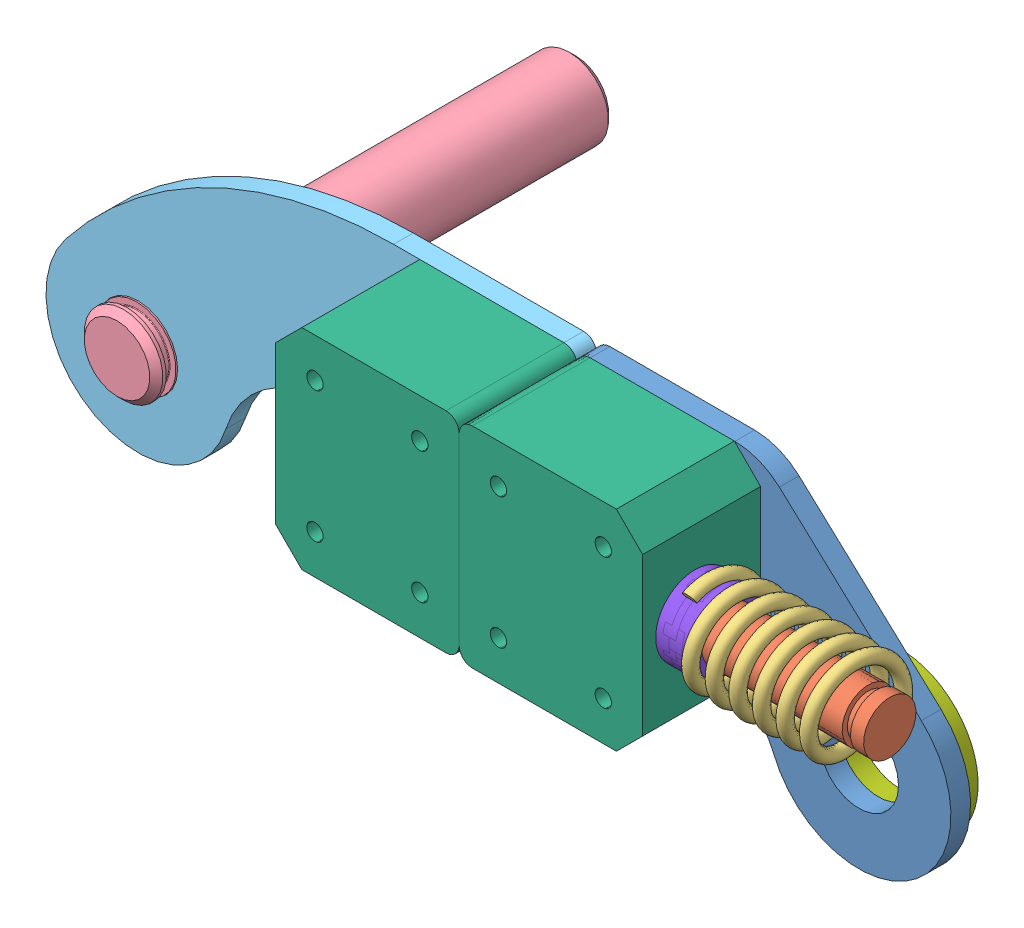
SolidWorks assembly Assem1-knee-mod2-front-mirror, configuration Défaut. Lengths in mm.
Overall size (71.29 24.64 43.49).
18 component instances, 10 part files, 31 mates.
Components (placement in the parent):
- Part1-knee-mod3-front-1: Part1-knee-mod3-front [Défaut] at (3.122 0.7472 0) size (28.52 23.53 1.5)
- part2-knee-mod1-1: part2-knee-mod1 [Default] at (-34.018 9.2472 5.75) x (0 0.169023 0.985612) z (0 0.985612 -0.169023) size (4 44.5 4)
- Spring_DF-1670-2: Spring_DF-1670 [Défaut] at (-2.378 9.2472 5.75) x (0 -0.202607 -0.97926) z (1 0 0) size (8.62 8.62 12.7)
- d5l35-1: d5l35 [Default] at (-51.878 0.7472 -32.65) x (1 0 0) z (0 -1 0) size (6 35 6)
- al_d6_1-2: al_d6_1 [Default] at (3.122 0.7472 -10.41) x (0.954097 0.299497 0) z (0.299497 -0.954097 0) size (6 13 6)
- lock washer for shafts_din-3: lock washer for shafts_din [PreviewCfg] at (-32.378 9.2472 5.75) x (0 0.148956 -0.988844) z (1 0 0) size (2.25 1.94 0.2)
- lock washer for shafts_din-4: lock washer for shafts_din [PreviewCfg] at (8.842 9.2472 5.75) x (0 -1 0) z (-1 0 0) size (2.25 1.94 0.2)
- lock washer for shafts_din-5: lock washer for shafts_din [PreviewCfg] at (-51.878 0.7472 1.05) size (2.25 1.94 0.2)
- lock washer for shafts_din-6: lock washer for shafts_din [PreviewCfg] at (3.122 0.7472 1.05) size (2.25 1.94 0.2)
- Part2-knee-mod3-front-1: Part2-knee-mod3-front [Défaut] at (-51.878 0.7472 0) x (-1 0 0) z (0 0 -1) size (40.53 23.53 1.5)
- part4-knee-mod1-1: part4-knee-mod1 [Défaut] at (-25.378 9.2472 5.75) x (0 1 0) z (-1 0 0) size (16 9 14)
- part4-knee-mod1-2: part4-knee-mod1 [Défaut] at (-11.378 9.2472 5.75) x (0 -1 0) z (1 0 0) size (16 9 14)
- Washer-d6p5-12-1: Washer-d6p5-12 [Défaut] at (-51.878 0.7472 -1.55) x (0.480416 0.877041 0) z (0 0 1) size (12 12 1.6)
- Washer-d6p5-12-2: Washer-d6p5-12 [Défaut] at (3.122 0.7472 -1.55) x (0.480416 0.877041 0) z (0 0 1) size (12 12 1.6)
- washer-m3-6-3-1-1: washer-m3-6-3-1 [Default] at (-4.378 9.2472 5.75) x (1 0 0) z (0 -0.999216 -0.039595) size (1 6 6)
- washer-m3-6-3-1-5: washer-m3-6-3-1 [Default] at (-3.878 9.2472 5.75) x (1 0 0) z (0 -0.999216 -0.039595) size (1 6 6)
- washer-m3-6-3-1-6: washer-m3-6-3-1 [Default] at (-3.378 9.2472 5.75) x (1 0 0) z (0 -0.999216 -0.039595) size (1 6 6)
- washer-m3-6-3-1-7: washer-m3-6-3-1 [Default] at (-2.878 9.2472 5.75) x (1 0 0) z (0 -0.999216 -0.039595) size (1 6 6)
Mates (geometry in assembly coordinates):
- Coaxiale19: concentric anti-aligned: cylinder of part2-knee-mod1-1 through (-34.018 9.2472 5.75) axis (-1 0 0) radius 2; line of Spring_DF-1670-2 through (-2.378 9.2472 5.75) axis (1 0 0)
- Coaxiale21: concentric aligned: cylinder of Part1-knee-mod3-front-1 through (3.122 0.7472 0.75) axis (0 0 -1) radius 3.025; cylinder of al_d6_1-2 through (3.122 0.7472 -10.41) axis (0 0 -1) radius 3
- Coïncidente21: coincident aligned: plane of d5l35-1 through (-51.878 4.3472 0.85) normal (0 0 1); plane of al_d6_1-2 through (2.3732 3.1324 0.85) normal (0 0 1)
- Coïncidente29: coincident anti-aligned: plane of part2-knee-mod1-1 through (-32.378 9.5176 7.327) normal (-1 0 0); plane of lock washer for shafts_din-3 through (-32.378 9.2472 5.75) normal (1 0 0)
- Coaxiale31: concentric aligned: cylinder of part2-knee-mod1-1 through (10.482 9.2472 5.75) axis (1 0 0) radius 1.6; cylinder of lock washer for shafts_din-3 through (-32.578 9.2472 5.75) axis (1 0 0) radius 0.4
- Coaxiale35: concentric anti-aligned: cylinder of part2-knee-mod1-1 through (10.482 9.2472 5.75) axis (1 0 0) radius 1.6; cylinder of lock washer for shafts_din-4 through (9.042 9.2472 5.75) axis (-1 0 0) radius 0.4
- Coïncidente30: coincident anti-aligned: plane of part2-knee-mod1-1 through (8.842 9.6148 7.8935) normal (1 0 0); plane of lock washer for shafts_din-4 through (8.842 9.2472 5.75) normal (-1 0 0)
- Coaxiale36: concentric anti-aligned: cylinder of d5l35-1 through (-51.878 0.7472 17.35) axis (0 0 -1) radius 2.5; cylinder of lock washer for shafts_din-5 through (-51.878 0.7472 0.85) axis (0 0 1) radius 0.4
- Coïncidente31: coincident anti-aligned: plane of d5l35-1 through (-51.878 4.3472 0.85) normal (0 0 1); plane of lock washer for shafts_din-5 through (-51.878 0.7472 0.85) normal (0 0 -1)
- Coaxiale37: concentric anti-aligned: cylinder of al_d6_1-2 through (3.122 0.7472 39.6188) axis (0 0 -1) radius 2.5; cylinder of lock washer for shafts_din-6 through (3.122 0.7472 0.85) axis (0 0 1) radius 0.4
- Coïncidente32: coincident anti-aligned: plane of al_d6_1-2 through (2.3732 3.1324 0.85) normal (0 0 1); plane of lock washer for shafts_din-6 through (3.122 0.7472 0.85) normal (0 0 -1)
- Coïncidente37: coincident anti-aligned: plane of Part1-knee-mod3-front-1 through (-18.378 17.2472 0.75) normal (-1 0 0); plane of Part2-knee-mod3-front-1 through (-18.378 17.2472 -0.75) normal (1 0 0)
- Coïncidente38: coincident aligned: plane of Part1-knee-mod3-front-1 through (3.122 0.7472 -0.75) normal (0 0 -1); plane of Part2-knee-mod3-front-1 through (-51.878 0.7472 -0.75) normal (0 0 -1)
- Coïncidente39: coincident aligned: plane of Part1-knee-mod3-front-1 through (-18.378 17.2472 0.75) normal (0 1 0); plane of Part2-knee-mod3-front-1 through (-18.378 17.2472 -0.75) normal (0 1 0)
- Coaxiale49: concentric anti-aligned: cylinder of d5l35-1 through (-51.878 0.7472 -32.65) axis (0 0 -1) radius 3; cylinder of Part2-knee-mod3-front-1 through (-51.878 0.7472 -0.75) axis (0 0 1) radius 3.025
- Distance10: distance = 0.1 mm aligned: plane of d5l35-1 through (-51.878 4.3472 0.85) normal (0 0 1); plane of Part2-knee-mod3-front-1 through (-51.878 0.7472 0.75) normal (0 0 1)
- Coïncidente40: coincident anti-aligned: plane of Part2-knee-mod3-front-1 through (-51.878 0.7472 0.75) normal (0 0 1); plane of part4-knee-mod1-1 through (-32.378 1.2472 0.75) normal (0 0 -1)
- Coaxiale52: concentric anti-aligned: cylinder of Part2-knee-mod3-front-1 through (-21.378 14.2472 -0.75) axis (0 0 1) radius 0.85; cylinder of part4-knee-mod1-1 through (-21.378 14.2472 0.75) axis (0 0 -1) radius 0.625
- Coaxiale53: concentric anti-aligned: cylinder of Part2-knee-mod3-front-1 through (-29.378 4.2472 -0.75) axis (0 0 1) radius 0.85; cylinder of part4-knee-mod1-1 through (-29.378 4.2472 0.75) axis (0 0 -1) radius 0.625
- Coïncidente41: coincident anti-aligned: plane of Part1-knee-mod3-front-1 through (3.122 0.7472 0.75) normal (0 0 1); plane of part4-knee-mod1-2 through (-4.378 17.2472 0.75) normal (0 0 -1)
- Coaxiale54: concentric aligned: cylinder of Part1-knee-mod3-front-1 through (-7.378 14.2472 0.75) axis (0 0 -1) radius 0.85; cylinder of part4-knee-mod1-2 through (-7.378 14.2472 0.75) axis (0 0 -1) radius 0.625
- Coaxiale55: concentric aligned: cylinder of Part1-knee-mod3-front-1 through (-15.378 4.2472 0.75) axis (0 0 -1) radius 0.85; cylinder of part4-knee-mod1-2 through (-15.378 4.2472 0.75) axis (0 0 -1) radius 0.625
- Coaxiale56: concentric anti-aligned: cylinder of part2-knee-mod1-1 through (-34.018 9.2472 5.75) axis (-1 0 0) radius 2; cylinder of part4-knee-mod1-1 through (-32.378 9.2472 5.75) axis (1 0 0) radius 2
- Coïncidente42: coincident anti-aligned: plane of lock washer for shafts_din-3 through (-32.378 9.2472 5.75) normal (1 0 0); plane of part4-knee-mod1-1 through (-32.378 1.2472 9.75) normal (-1 0 0)
- Distance11: distance = 2 mm aligned: plane of Spring_DF-1670-2 through (-2.378 9.2472 5.75) normal (1 0 0); plane of part4-knee-mod1-2 through (-4.378 17.2472 9.75) normal (1 0 0)
- Concentric28: concentric anti-aligned: cylinder of Part2-knee-mod3-front-1 through (-51.878 0.7472 -0.75) axis (0 0 1) radius 7.025; cylinder of Washer-d6p5-12-1 through (-51.878 0.7472 -0.75) axis (0 0 -1) radius 6
- Coincident10: coincident anti-aligned: plane of Part2-knee-mod3-front-1 through (-51.878 0.7472 -0.75) normal (0 0 -1); plane of Washer-d6p5-12-1 through (-51.878 0.7472 -0.75) normal (0 0 1)
- Concentric29: concentric aligned: cylinder of al_d6_1-2 through (3.122 0.7472 -10.41) axis (0 0 -1) radius 3; cylinder of Washer-d6p5-12-2 through (3.122 0.7472 -0.75) axis (0 0 -1) radius 6
- Coincident12: coincident anti-aligned: plane of Part1-knee-mod3-front-1 through (3.122 0.7472 -0.75) normal (0 0 -1); plane of Washer-d6p5-12-2 through (3.122 0.7472 -0.75) normal (0 0 1)
- Coïncidente43: coincident anti-aligned: plane of part4-knee-mod1-2 through (-4.378 17.2472 9.75) normal (1 0 0); plane of washer-m3-6-3-1-1 through (-4.378 9.1284 8.7476) normal (-1 0 0)
- Coaxiale57: concentric aligned: cylinder of part2-knee-mod1-1 through (-34.018 9.2472 5.75) axis (-1 0 0) radius 2; cylinder of washer-m3-6-3-1-1 through (-4.378 9.2472 5.75) axis (-1 0 0) radius 1.5
